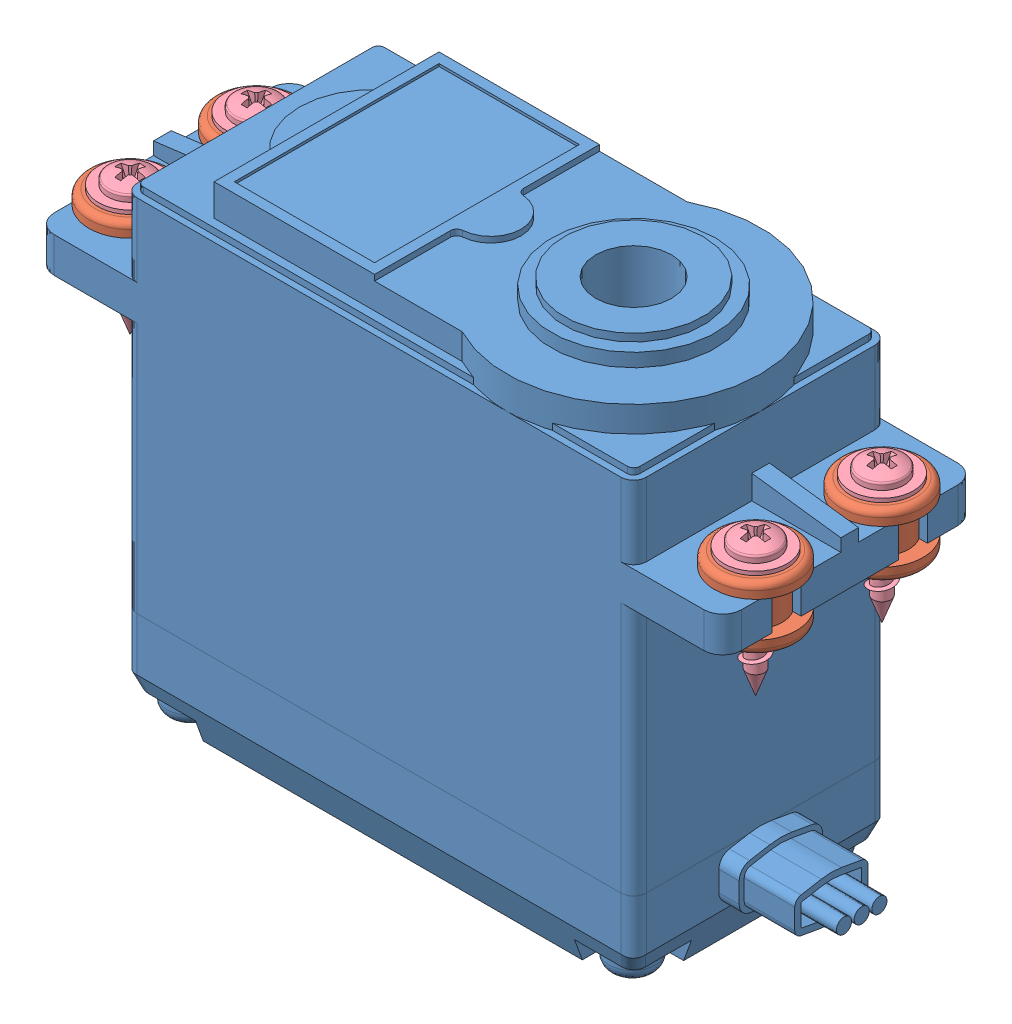
SolidWorks assembly FS5109M_Ensemble corps, configuration Défaut. Lengths in mm.
Overall size (56.15 39.9 20.1).
17 component instances, 4 part files, 11 mates.
Components (placement in the parent):
- FS5109M_corps-1: FS5109M_corps [Défaut] at origin size (55.35 39.9 20.1)
- FS5109M_Ensemble silent-bloc-1: FS5109M_Ensemble silent-bloc [Défaut] at (-24.75 1.4 5) size (6.5 5.2 6.5)
  - FS5109M_silent-bloc-1: FS5109M_silent-bloc [Défaut] at origin size (6.5 5 6.5)
  - FS5109M_silent-bloc_douille-1: FS5109M_silent-bloc_douille [Défaut] at (0 -2.7 0) x (-1 0 0) z (0 0 1) size (4.5 5.2 4.5)
- FS5109M_Ensemble silent-bloc-2: FS5109M_Ensemble silent-bloc [Défaut] at (-24.75 1.4 -5) size (6.5 5.2 6.5)
  - FS5109M_silent-bloc-1: FS5109M_silent-bloc [Défaut] at origin size (6.5 5 6.5)
  - FS5109M_silent-bloc_douille-1: FS5109M_silent-bloc_douille [Défaut] at (0 -2.7 0) x (-1 0 0) z (0 0 1) size (4.5 5.2 4.5)
- FS5109M_Ensemble silent-bloc-3: FS5109M_Ensemble silent-bloc [Défaut] at (24.75 1.4 -5) x (-1 0 0) z (0 0 -1) size (6.5 5.2 6.5)
  - FS5109M_silent-bloc-1: FS5109M_silent-bloc [Défaut] at origin size (6.5 5 6.5)
  - FS5109M_silent-bloc_douille-1: FS5109M_silent-bloc_douille [Défaut] at (0 -2.7 0) x (-1 0 0) z (0 0 1) size (4.5 5.2 4.5)
- FS5109M_Ensemble silent-bloc-4: FS5109M_Ensemble silent-bloc [Défaut] at (24.75 1.4 5) x (-1 0 0) z (0 0 -1) size (6.5 5.2 6.5)
  - FS5109M_silent-bloc-1: FS5109M_silent-bloc [Défaut] at origin size (6.5 5 6.5)
  - FS5109M_silent-bloc_douille-1: FS5109M_silent-bloc_douille [Défaut] at (0 -2.7 0) x (-1 0 0) z (0 0 1) size (4.5 5.2 4.5)
- FS5109M_vis servo 2 x 10-1: FS5109M_vis servo 2 x 10 [ISO 7045 - M2 x 10 - Z --- 10N] at (-24.75 5.2 5) x (0 -1 0) z (0 0 -1) size (11.27 5 5)
- FS5109M_vis servo 2 x 10-2: FS5109M_vis servo 2 x 10 [ISO 7045 - M2 x 10 - Z --- 10N] at (-24.75 5.2 -5) x (0 -1 0) z (0 0 -1) size (11.27 5 5)
- FS5109M_vis servo 2 x 10-3: FS5109M_vis servo 2 x 10 [ISO 7045 - M2 x 10 - Z --- 10N] at (24.75 5.2 -5) x (0 -1 0) z (0 0 1) size (11.27 5 5)
- FS5109M_vis servo 2 x 10-4: FS5109M_vis servo 2 x 10 [ISO 7045 - M2 x 10 - Z --- 10N] at (24.75 5.2 5) x (0 -1 0) z (0 0 1) size (11.27 5 5)
Mates (geometry in assembly coordinates):
- Coïncidente1: coordinate: point of FS5109M_corps-1; point of assembly
- Coaxiale1: concentric anti-aligned: cylinder of FS5109M_corps-1 through (-24.75 -27.1 5) axis (0 1 0) radius 2.125; cylinder of FS5109M_Ensemble silent-bloc-1/FS5109M_silent-bloc-1 through (-24.75 1.4 5) axis (0 -1 0) radius 2.13
- Coïncidente2: coincident anti-aligned: plane of FS5109M_corps-1 through (-27.2 2.8 10.05) normal (0 1 0); plane of FS5109M_Ensemble silent-bloc-1/FS5109M_silent-bloc-1 through (-28 2.8 5) normal (0 -1 0)
- Coaxiale2: concentric anti-aligned: cylinder of FS5109M_corps-1 through (-24.75 -27.1 -5) axis (0 1 0) radius 2.125; circle of FS5109M_Ensemble silent-bloc-2/FS5109M_silent-bloc-1
- Coïncidente3: coincident aligned: plane of FS5109M_Ensemble silent-bloc-1/FS5109M_silent-bloc-1 through (-24.75 1.4 5) normal (0 1 0); plane of FS5109M_Ensemble silent-bloc-2/FS5109M_silent-bloc-1 through (-24.75 1.4 -5) normal (0 1 0)
- Coïncidente4: coincident aligned: plane of FS5109M_Ensemble silent-bloc-1/FS5109M_silent-bloc-1 through (-24.75 1.4 5) normal (1 0 0); plane of FS5109M_Ensemble silent-bloc-2/FS5109M_silent-bloc-1 through (-24.75 1.4 -5) normal (1 0 0)
- Coaxiale3: concentric aligned: cylinder of FS5109M_Ensemble silent-bloc-1/FS5109M_silent-bloc_douille-1 through (-24.75 -1.3 5) axis (0 -1 0) radius 1.28; line of FS5109M_vis servo 2 x 10-1 through (-24.75 5.2 5) axis (0 -1 0)
- Coaxiale4: concentric aligned: cylinder of FS5109M_Ensemble silent-bloc-2/FS5109M_silent-bloc_douille-1 through (-24.75 -1.3 -5) axis (0 -1 0) radius 1.28; line of FS5109M_vis servo 2 x 10-2 through (-24.75 5.2 -5) axis (0 -1 0)
- Coïncidente6: coincident aligned: plane of FS5109M_vis servo 2 x 10-1; plane of FS5109M_vis servo 2 x 10-2
- Coïncidente7: coincident aligned: plane of FS5109M_vis servo 2 x 10-1; plane of FS5109M_vis servo 2 x 10-2
- Coïncidente8: coincident anti-aligned: plane of FS5109M_Ensemble silent-bloc-1/FS5109M_silent-bloc-1 through (-27.5 3.9 5) normal (0 1 0); plane of FS5109M_vis servo 2 x 10-1 through (-25.45 3.9 5) normal (0 -1 0)
